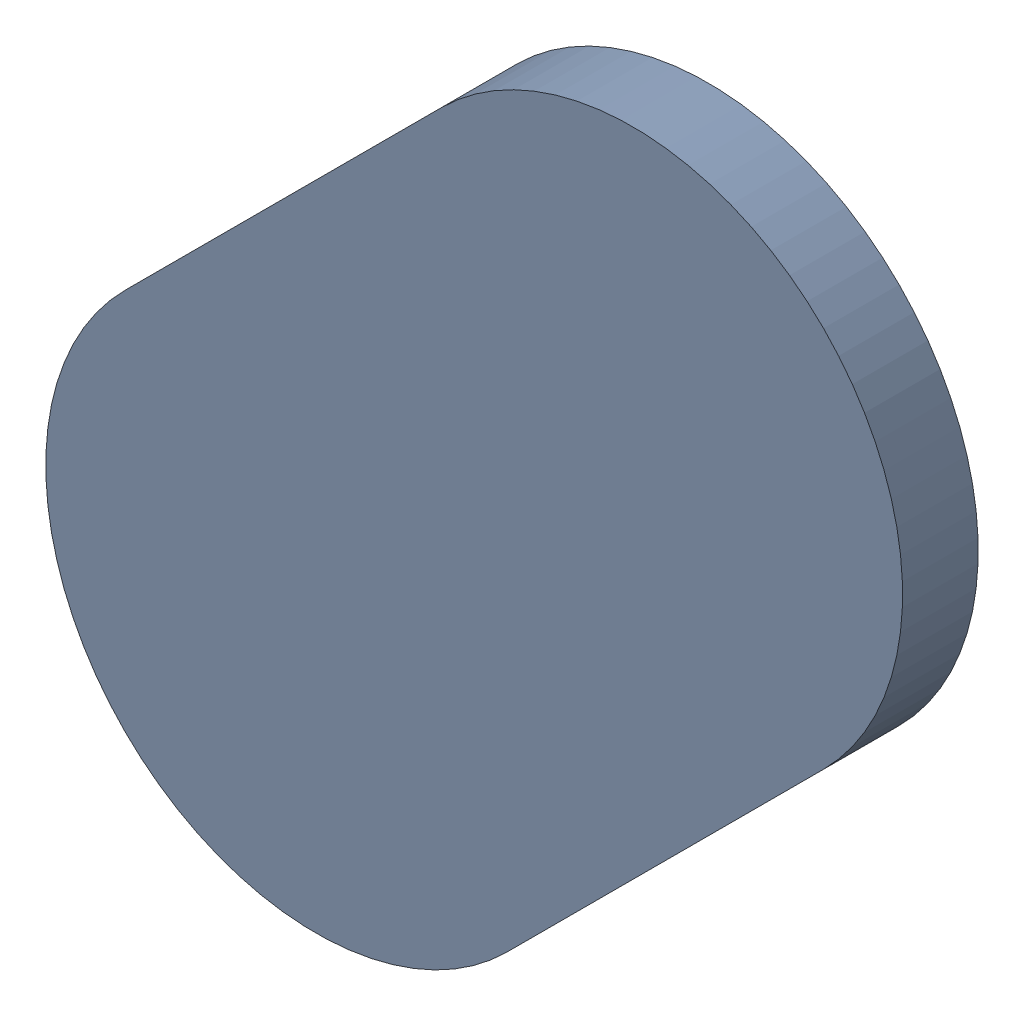
SolidWorks assembly Track (11.2mm,49.951mm)(11.349mm,50.1mm) on Top Layer, configuration Predeterminado. Lengths in mm.
Overall size (0.4 0.4 0.04).
2 component instances, 1 part files, 0 mates.
Components (placement in the parent):
- Track (11.2mm,49.951mm)(11.349mm,50.1mm) on Top Layer-1-1: Track (11.2mm,49.951mm)(11.349mm,50.1mm) on Top Layer-1 [Predeterminado] at (-68.317 -44.187 -0.0457) size (0.4 0.4 0.04)
  - Track (11.2mm,49.951mm)(11.349mm,50.1mm) on Top Layer-Part-1-1: Track (11.2mm,49.951mm)(11.349mm,50.1mm) on Top Layer-Part-1 [Predeterminado] at origin size (0.4 0.4 0.04)
